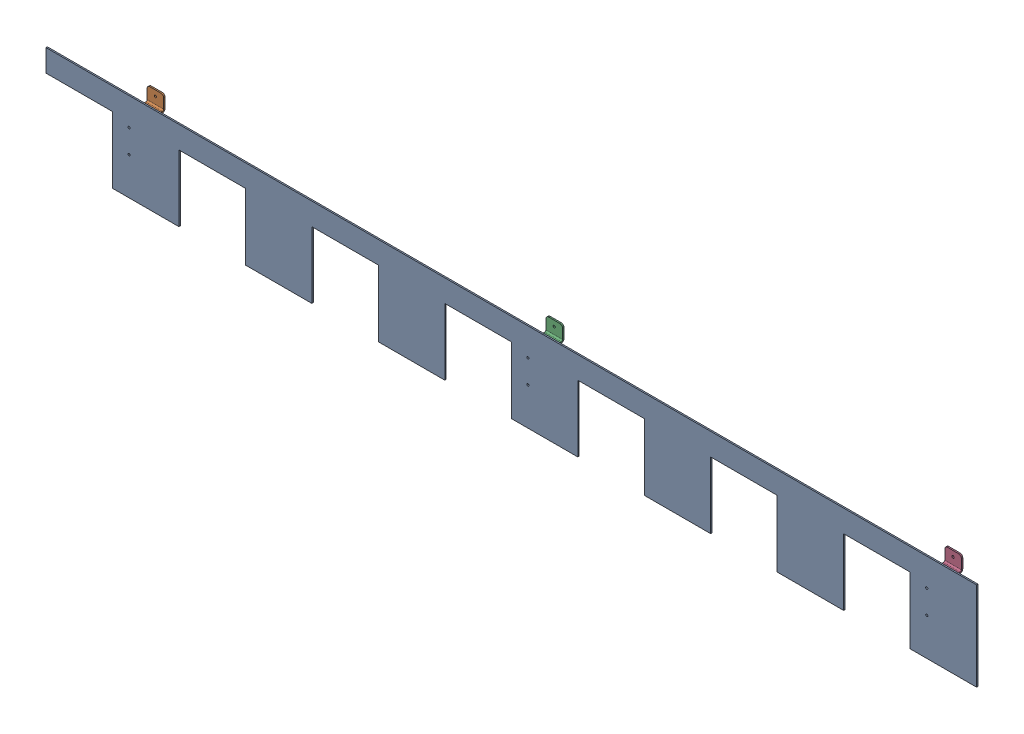
SolidWorks assembly GE-16129_ASM, configuration Default. Lengths in mm.
Overall size (2133.6 203.2 63.5).
4 component instances, 2 part files, 0 mates.
Components (placement in the parent):
- GE-16130-1: GE-16130 [Default] at origin size (2133.6 203.2 3.17)
- GE-16135-1: GE-16135 [Default] at (-876.3 50.8 0) x (-1 0 0) z (0 1 0) size (38.1 60.32 107.95)
- GE-16135-2: GE-16135 [Default] at (38.1 50.8 0) x (-1 0 0) z (0 1 0) size (38.1 60.32 107.95)
- GE-16135-3: GE-16135 [Default] at (952.5 50.8 0) x (-1 0 0) z (0 1 0) size (38.1 60.32 107.95)
